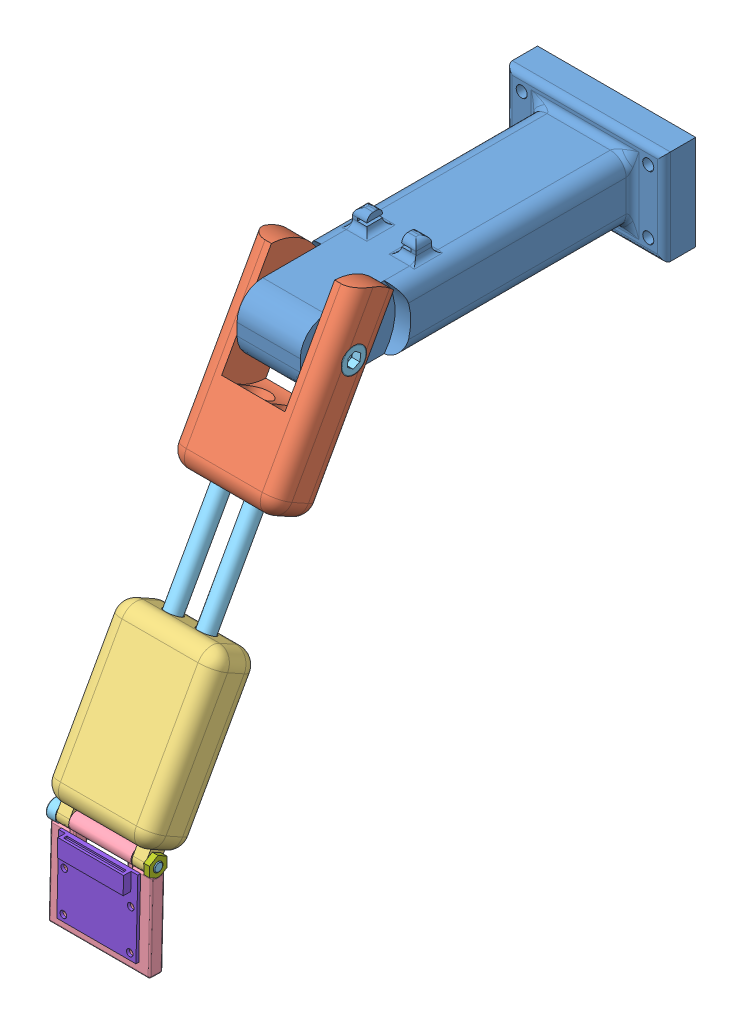
SolidWorks assembly ass_support_cam, configuration Défaut. Lengths in mm.
Overall size (50 159.69 177.38).
19 component instances, 13 part files, 28 mates.
Components (placement in the parent):
- pied1-1: pied1 [Défaut] at (-30.7984 -12.2569 55) size (50 30 110)
- pied2_1-1: pied2_1 [Défaut] at (-22.7984 4.1803 137.0296) x (0 -0.873622 0.486605) z (0 0.486605 0.873622) size (58.03 34 16)
- pied2_2-1: pied2_2 [Défaut] at (11.2033 -110.9245 201.1427) x (0 0.873622 -0.486605) z (0 0.486605 0.873622) size (55.5 34 16)
- support_cameraAdjustCam-1: support_cameraAdjustCam [Défaut] at (10.0533 -98.2001 218.0539) x (0 0.553621 -0.832768) z (-1 0 0) size (20.86 27.59 32)
- socket head cap screw 4762_din-5: socket head cap screw 4762_din [EN ISO 4762 M5 x 30 - 22N] at (11.2016 2.7431 155) x (-1 0 0) z (0 -0.924104 -0.382141) size (35 8.5 8.5)
- socket head cap screw 4762_din-6: socket head cap screw 4762_din [EN ISO 4762 M5 x 50 - 22N] at (-0.5252 -23.4655 169.5982) x (0 -0.873622 0.486605) z (-0.846275 0.259238 0.46542) size (55 8.5 8.5)
- socket head cap screw 4762_din-7: socket head cap screw 4762_din [EN ISO 4762 M5 x 50 - 22N] at (-11.0717 -23.4655 169.5982) x (0 -0.873622 0.486605) z (-0.940242 0.165693 0.297475) size (55 8.5 8.5)
- hex nut style 1 gradeab_din-1: hex nut style 1 gradeab_din [Hexagon Nut ISO 4032 - M5 - W - N] at (-11.0717 -68.4185 194.6368) x (1 0 0) z (0 -0.873622 0.486605) size (8 9.24 4.7)
- hex nut style 1 gradeab_din-2: hex nut style 1 gradeab_din [Hexagon Nut ISO 4032 - M5 - W - N] at (-0.5252 -68.4185 194.6368) x (0.969475 -0.119312 -0.214205) z (0 -0.873622 0.486605) size (8 9.24 4.7)
- socket head cap screw 4762_din-8: socket head cap screw 4762_din [EN ISO 4762 M3 x 30 - 18N] at (-22.7967 -106.2463 215.7068) x (1 0 0) z (0 0.861826 0.507204) size (33 5.5 5.5)
- hex thin nut gradeb_din-1: hex thin nut gradeb_din [Hexagon Nut ISO 4036 - M3 - N] at (10.0033 -106.2463 215.7068) x (0 0.873622 -0.486605) z (1 0 0) size (5.5 6.35 1.8)
- RasPi_Camera-1: RasPi_Camera [FOV] at (-5.9467 -118.2406 217.4933) x (-1 0 0) z (0 -0.999708 0.024156) size (25 8.25 24)
  - RasPi_Camera_Board-1: RasPi_Camera_Board [Standard] at (0 -0.5517 0) x (-1 0 0) z (0 0 -1) size (25 3.5 24)
  - OVA5647-2: OVA5647 [FOV] at (0.0315 -0.3517 0.0586) size (8 5.3 16.75)
    - OVA5647-1: OVA5647 [Standard] at (0.32 0 -0.175) size (8 0.68 8)
    - OVA5647_Housing-1: OVA5647_Housing [Standard] at origin size (8 3.95 8)
    - OVA5647_IR-Glas-1: OVA5647_IR-Glas [Standard] at (0 0.95 0) x (-1 0 0) z (0 0 1) size (6.3 0.35 6.3)
    - OVA5647_Lens-1: OVA5647_Lens [FOV] at (0 3.95 0) size (6 3.35 6)
    - OVA5647_Pigtail-1: OVA5647_Pigtail [Standard] at origin size (8 1.3 16.75)
Mates (geometry in assembly coordinates):
- Coaxiale1: concentric anti-aligned: cylinder of pied1-1 through (19.2016 2.7431 155) axis (-1 0 0) radius 2.75; cylinder of pied2_1-1 through (-22.7984 2.7431 155) axis (1 0 0) radius 2.75
- Coïncidente1: coincident: plane of pied1-1 through (-15.7984 2.7431 151.2803) normal (-1 0 0); line of pied2_1-1 through (-15.7984 0.732 172.9152) axis (0 0.888737 -0.458418)
- Coaxiale2: concentric anti-aligned: cylinder of pied2_1-1 through (-11.0717 -32.2018 174.4642) axis (0 0.873622 -0.486605) radius 2.75; cylinder of pied2_2-1 through (-11.0717 -59.9443 189.9167) axis (0 -0.873622 0.486605) radius 2.75
- Coaxiale5: concentric aligned: cylinder of pied2_2-1 through (-15.7967 -106.2463 215.7068) axis (-1 0 0) radius 1.5; cylinder of support_cameraAdjustCam-1 through (10.0533 -106.2463 215.7068) axis (-1 0 0) radius 1.7
- Coïncidente2: coincident anti-aligned: plane of pied2_2-1 through (-15.7967 -106.2463 215.7068) normal (1 0 0); plane of support_cameraAdjustCam-1 through (-15.7967 -106.2463 215.7068) normal (-1 0 0)
- Coïncidente3: coincident aligned: plane of pied2_1-1 through (11.2016 22.3854 153.2166) normal (0 0.486605 0.873622); plane of pied2_2-1 through (11.2033 -56.0515 196.9057) normal (0 0.486605 0.873622)
- Coïncidente4: coincident anti-aligned: plane of pied1-1 through (-15.7984 2.7431 151.2803) normal (-1 0 0); plane of pied2_1-1 through (-15.7984 2.7431 155) normal (1 0 0)
- Coaxiale7: concentric anti-aligned: cylinder of pied1-1 through (19.2016 2.7431 155) axis (-1 0 0) radius 2.75; cylinder of socket head cap screw 4762_din-5 through (42.9516 2.7431 155) axis (1 0 0) radius 2.5
- Coïncidente6: coincident anti-aligned: plane of pied2_1-1 through (6.2016 2.7431 155) normal (1 0 0); plane of socket head cap screw 4762_din-5 through (6.2016 4.3672 151.0726) normal (-1 0 0)
- Coaxiale9: concentric aligned: cylinder of pied2_1-1 through (-11.0717 -32.2018 174.4642) axis (0 0.873622 -0.486605) radius 2.75; cylinder of socket head cap screw 4762_din-7 through (-11.0717 4.272 154.1484) axis (0 0.873622 -0.486605) radius 2.5
- Coaxiale10: concentric aligned: cylinder of pied2_1-1 through (-0.5252 -32.2018 174.4642) axis (0 0.873622 -0.486605) radius 2.75; cylinder of socket head cap screw 4762_din-6 through (-0.5252 4.272 154.1484) axis (0 0.873622 -0.486605) radius 2.5
- Coïncidente8: coincident anti-aligned: plane of pied2_1-1 through (-11.0717 -27.8337 172.0312) normal (0 0.873622 -0.486605); plane of socket head cap screw 4762_din-7 through (-9.6246 -25.8892 175.5222) normal (0 -0.873622 0.486605)
- Coïncidente9: coincident anti-aligned: plane of pied2_1-1 through (-0.5252 -27.8337 172.0312) normal (0 0.873622 -0.486605); plane of socket head cap screw 4762_din-6 through (1.739 -26.0835 175.1733) normal (0 -0.873622 0.486605)
- Coaxiale11: concentric anti-aligned: cylinder of socket head cap screw 4762_din-7 through (-11.0717 4.272 154.1484) axis (0 0.873622 -0.486605) radius 2.5; cylinder of hex nut style 1 gradeab_din-1 through (-11.0717 -64.3124 192.3498) axis (0 -0.873622 0.486605) radius 2.1
- Coaxiale12: concentric anti-aligned: cylinder of socket head cap screw 4762_din-6 through (-0.5252 4.272 154.1484) axis (0 0.873622 -0.486605) radius 2.5; cylinder of hex nut style 1 gradeab_din-2 through (-0.5252 -64.3124 192.3498) axis (0 -0.873622 0.486605) radius 2.1
- Coïncidente10: coincident anti-aligned: plane of pied2_2-1 through (11.2033 -71.6115 179.2454) normal (0 -0.873622 0.486605); plane of hex nut style 1 gradeab_din-2 through (-8.2809 -63.3579 194.0634) normal (0 0.873622 -0.486605)
- Coïncidente11: coincident anti-aligned: plane of pied2_2-1 through (11.2033 -71.6115 179.2454) normal (0 -0.873622 0.486605); plane of hex nut style 1 gradeab_din-1 through (-19.0717 -64.3124 192.3498) normal (0 0.873622 -0.486605)
- Distance1: distance = 27.0125 mm anti-aligned: plane of pied2_2-1 through (11.2033 -52.6452 203.0211) normal (0 0.873622 -0.486605); plane of pied2_1-1 through (-22.7984 -24.9027 187.5685) normal (0 -0.873622 0.486605)
- Verrouiller1: lock: unknown of pied1-1; unknown of pied2_1-1
- Verrouiller2: lock: unknown of pied2_2-1; unknown of support_cameraAdjustCam-1
- Coaxiale13: concentric anti-aligned: cylinder of pied2_2-1 through (4.2033 -106.2463 215.7068) axis (1 0 0) radius 1.5; cylinder of socket head cap screw 4762_din-8 through (-54.5467 -106.2463 215.7068) axis (-1 0 0) radius 1.5
- Coïncidente18: coincident anti-aligned: plane of pied2_2-1 through (-19.7967 -110.9245 201.1427) normal (-1 0 0); plane of socket head cap screw 4762_din-8 through (-19.7967 -104.8515 213.3368) normal (1 0 0)
- Coaxiale15: concentric anti-aligned: cylinder of socket head cap screw 4762_din-8 through (-54.5467 -106.2463 215.7068) axis (-1 0 0) radius 1.5; cylinder of hex thin nut gradeb_din-1 through (8.2033 -106.2463 215.7068) axis (1 0 0) radius 1.25
- Parallèle4: parallel anti-aligned: plane of pied2_2-1 through (11.2033 -96.3263 227.3513) normal (0 -0.873622 0.486605); plane of hex thin nut gradeb_din-1 through (8.2033 -103.0712 215.7557) normal (0 0.873622 -0.486605)
- Coïncidente20: coincident anti-aligned: plane of pied2_2-1 through (8.2033 -110.9245 201.1427) normal (1 0 0); plane of hex thin nut gradeb_din-1 through (8.2033 -104.7011 218.4809) normal (-1 0 0)
- Coaxiale16: concentric anti-aligned: cylinder of support_cameraAdjustCam-1 through (-16.4467 -119.3889 169.9704) axis (0 0.024156 0.999708) radius 1.25; cylinder of RasPi_Camera-1/RasPi_Camera_Board-1 through (-16.4467 -118.2055 218.9445) axis (0 -0.024156 -0.999708) radius 1.05
- Parallèle5: parallel aligned: plane of support_cameraAdjustCam-1 through (-21.9467 -98.2001 218.0539) normal (-1 0 0); plane of RasPi_Camera-1/RasPi_Camera_Board-1 through (-18.4467 -132.7013 219.2948) normal (-1 0 0)
- Coïncidente21: coincident anti-aligned: plane of support_cameraAdjustCam-1 through (-21.9467 -107.6303 217.7887) normal (0 0.024156 0.999708); plane of RasPi_Camera-1/RasPi_Camera_Board-1 through (-5.9467 -118.2272 218.0448) normal (0 -0.024156 -0.999708)
